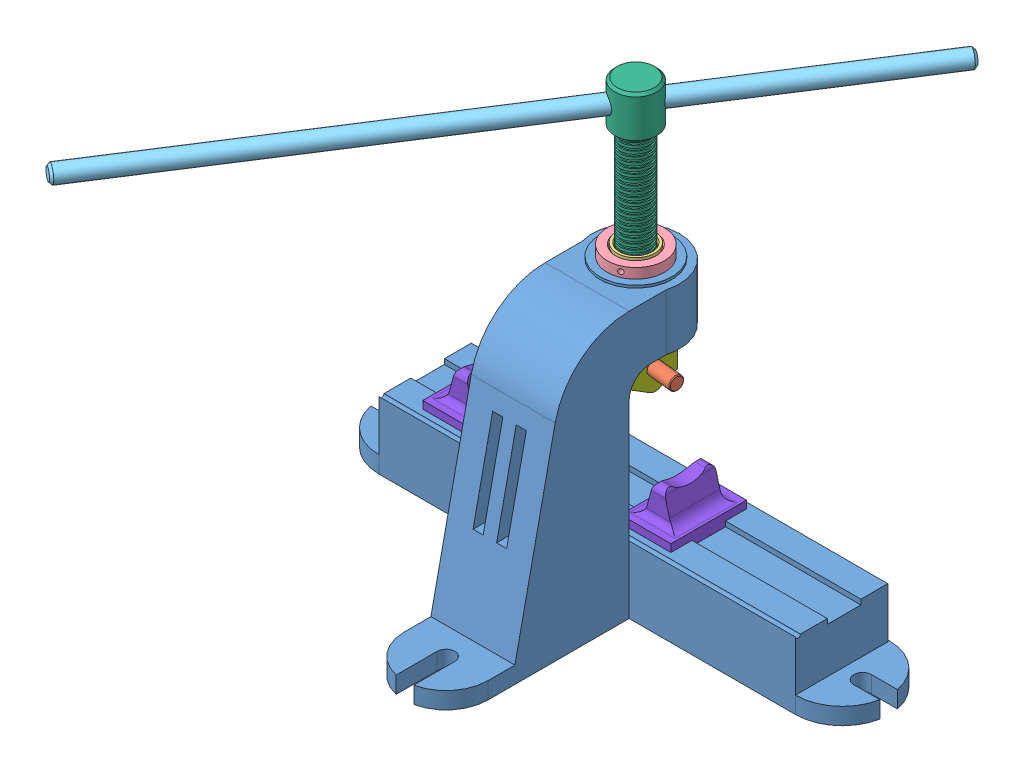
SolidWorks assembly Assem1, configuration Default. Lengths in mm.
Overall size (606.01 504.5 686.52).
9 component instances, 8 part files, 20 mates.
Components (placement in the parent):
- part1___-1: part1___ [Default] at (253.6651 237.3221 504.3021) size (606.01 320 328.89)
- part2__-1: part2__ [Default] at (308.3622 455.8221 510.0668) x (0.994492 0 0.104812) z (-0.0912 -0.492822 0.865337) size (40 16 16)
- Part4-1: Part4 [Default] at (253.6651 481.3221 504.3021) x (0.000718 0 1) z (-1 0 0.000718) size (65 90 65)
- part5-1: part5 [Default] at (253.6651 563.3221 504.3021) x (0.919487 0 -0.39312) z (0.39312 0 0.919487) size (68 12 68.06)
- Part6-1: Part6 [Default] at (412.3291 717.8221 257.6373) x (-0.540984 0 0.841033) z (0.797394 0.317936 0.512913) size (800 20 20)
- Part7__-1: Part7__ [Default] at (253.6651 741.8221 504.3021) x (-0.540984 0 0.841033) z (-0.841033 0 -0.540984) size (50 290 50)
- part8-1: part8 [Default] at (253.6651 480.8221 504.3021) x (0.104812 0 -0.994492) z (0.994492 0 0.104812) size (50 50 50)
- part9__-1: part9__ [Default] at (74.9587 311.3221 504.3021) size (60 50 90)
- part9__-3: part9__ [Default] at (310.455 311.3221 504.3021) size (60 50 90)
Mates (geometry in assembly coordinates):
- Concentric1: concentric anti-aligned: cylinder of Part6-1 through (659.6318 717.8221 -126.8285) axis (0.540984 0 -0.841033) radius 10; cylinder of Part7__-1 through (276.116 717.8221 469.3992) axis (-0.540984 0 0.841033) radius 10
- Concentric5: concentric anti-aligned: cylinder of part2__-1 through (194.2104 455.8221 498.036) axis (-0.994492 0 -0.104812) radius 4; cylinder of part8-1 through (228.8018 455.8221 501.6817) axis (0.994492 0 0.104812) radius 4
- Coincident3: coincident anti-aligned: circle of part2__-1; plane of part8-1 through (278.5274 440.8221 506.9224) normal (0.994492 0 0.104812)
- Concentric6: concentric aligned: cylinder of Part7__-1 through (253.6651 797.8518 504.3021) axis (0 1 0) radius 14; cylinder of part8-1 through (253.6651 451.8221 504.3021) axis (0 1 0) radius 14
- Coincident4: coincident anti-aligned: plane of Part7__-1 through (246.0914 451.8221 516.0765) normal (0 -1 0); plane of part8-1 through (253.6651 451.8221 504.3021) normal (0 1 0)
- Coincident7: coincident anti-aligned: plane of part1___-1 through (303.6651 311.3221 484.3021) normal (0 1 0); plane of part9__-1 through (104.9587 311.3221 524.3021) normal (0 -1 0)
- Coincident8: coincident anti-aligned: plane of part1___-1 through (303.6651 317.3221 484.3021) normal (0 0 1); plane of part9__-1 through (104.9587 311.3221 484.3021) normal (0 0 -1)
- Coincident9: coincident anti-aligned: plane of part1___-1 through (303.6651 311.3221 484.3021) normal (0 1 0); plane of part9__-3 through (340.455 311.3221 524.3021) normal (0 -1 0)
- Coincident10: coincident anti-aligned: plane of part1___-1 through (303.6651 317.3221 484.3021) normal (0 0 1); plane of part9__-3 through (340.455 311.3221 484.3021) normal (0 0 -1)
- LimitDistance1: limit distance = 161.2102 mm aligned: plane of part9__-3 through (340.455 311.3221 504.3021) normal (1 0 0); plane of part1___-1 through (501.6651 237.3221 504.3021) normal (1 0 0)
- LimitDistance2: limit distance = 396.7065 mm aligned: plane of part9__-1 through (104.9587 311.3221 504.3021) normal (1 0 0); plane of part1___-1 through (501.6651 237.3221 504.3021) normal (1 0 0)
- LimitDistance3: limit distance = 175.4963 mm anti-aligned: plane of part9__-1 through (104.9587 311.3221 504.3021) normal (1 0 0); plane of part9__-3 through (280.455 311.3221 504.3021) normal (-1 0 0)
- LimitDistance5: limit distance = 293.2879 mm anti-aligned: plane of Part6-1 through (412.3291 717.8221 257.6373) normal (0.540984 0 -0.841033); plane of Part7__-1 through (253.6651 741.8221 504.3021) normal (-0.540984 0 0.841033)
- Concentric16: concentric aligned: cylinder of part1___-1 through (253.6651 237.3211 504.3021) axis (0 1 0) radius 24; cylinder of Part4-1 through (253.6651 544.8839 504.3021) axis (0 1 0) radius 24
- Coincident18: coincident anti-aligned: plane of part1___-1 through (253.6651 491.3221 504.3021) normal (0 -1 0); plane of Part4-1 through (253.6885 491.3221 536.8021) normal (0 1 0)
- Concentric17: concentric aligned: cylinder of Part4-1 through (253.6651 544.8839 504.3021) axis (0 1 0) radius 22.5; cylinder of part5-1 through (253.6651 604.9257 504.3021) axis (0 1 0) radius 34
- Coincident19: coincident anti-aligned: plane of part1___-1 through (253.6651 557.3221 504.3021) normal (0 1 0); plane of part5-1 through (222.4026 557.3221 517.6682) normal (0 -1 0)
- Screw1: screw = 1 mm aligned: cylinder of Part4-1 through (253.6651 544.8839 504.3021) axis (0 1 0) radius 18; cylinder of Part7__-1 through (253.6651 797.8518 504.3021) axis (0 1 0) radius 18
- LimitDistance6: limit distance = 0.5 mm anti-aligned: plane of Part4-1 through (253.678 481.3221 522.3021) normal (0 -1 0); plane of part8-1 through (275.9071 480.8221 531.7847) normal (0 1 0)
- Lock6: lock: unknown of Part6-1; unknown of Part7__-1
